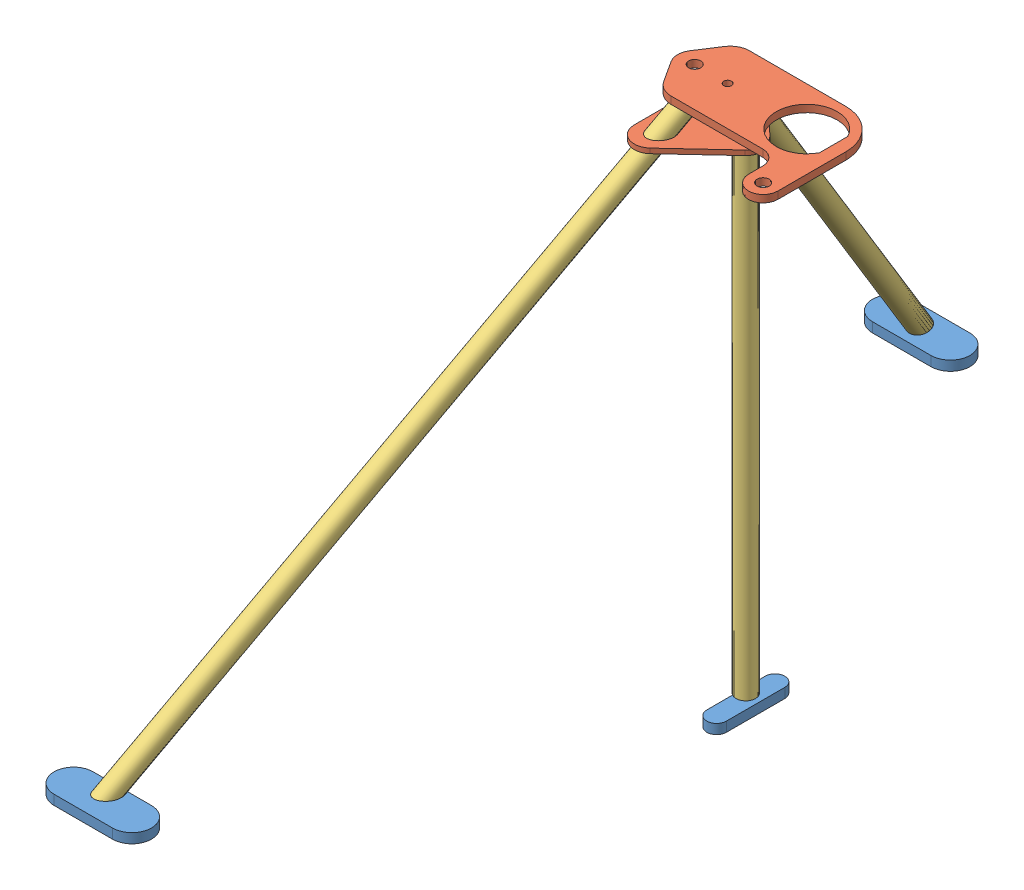
SolidWorks assembly RakedSensorMast, configuration Default. Lengths in mm.
Overall size (249.4 347.66 549.27).
4 component instances, 4 part files, 9 mates.
Components (placement in the parent):
- RakedSensorMastFeet-1: RakedSensorMastFeet [Default] x (-1 0 0) z (0 0 -1) size (190.5 342.9 549.27)
- RakedSensorMastTop-1: RakedSensorMastTop [Plates] x (-1 0 0) z (0 0 -1) size (109.7 26.99 94.83)
- RakedSensorMastTubes-1: RakedSensorMastTubes [Default] x (-1 0 0) z (0 0 -1) size (164.33 336.55 544.52)
- 91115A152_18-8 SS FEM THRDED HEX STANDOFF-1: 91115A152_18-8 SS FEM THRDED HEX STANDOFF [91115A151] at (-11.8541 -9.525 0) x (0 0 1) z (0 -1 0) size (6.35 7.33 19.71)
Mates (geometry in assembly coordinates):
- Concentric1: concentric anti-aligned: cylinder of RakedSensorMastFeet-1 through (-161.5757 -360.2726 -284.7157) axis (0.294384 0.76109 0.577997) radius 9.525; cylinder of RakedSensorMastTubes-1 through (-13.9451 21.4065 5.1443) axis (-0.294384 -0.76109 -0.577997) radius 6.35
- Concentric2: concentric anti-aligned: cylinder of RakedSensorMastFeet-1 through (-161.5757 -360.2726 284.7157) axis (0.294384 0.76109 -0.577997) radius 9.525; cylinder of RakedSensorMastTubes-1 through (-13.9451 21.4065 -5.1443) axis (-0.294384 -0.76109 0.577997) radius 6.35
- Concentric3: concentric anti-aligned: cylinder of RakedSensorMastTop-1 through (-36.4339 -36.7351 39.0104) axis (0.294384 0.76109 -0.577997) radius 6.35; cylinder of RakedSensorMastTubes-1 through (-13.9451 21.4065 -5.1443) axis (-0.294384 -0.76109 0.577997) radius 6.35
- Concentric4: concentric anti-aligned: cylinder of RakedSensorMastTop-1 through (-36.4339 -36.7351 -39.0104) axis (0.294384 0.76109 0.577997) radius 6.35; cylinder of RakedSensorMastTubes-1 through (-13.9451 21.4065 5.1443) axis (-0.294384 -0.76109 -0.577997) radius 6.35
- Concentric5: concentric anti-aligned: circle of RakedSensorMastTop-1; circle of 91115A152_18-8 SS FEM THRDED HEX STANDOFF-1
- Coincident1: coincident anti-aligned: plane of RakedSensorMastTop-1 through (0 -19.05 0) normal (0 1 0); plane of 91115A152_18-8 SS FEM THRDED HEX STANDOFF-1 through (-15.5202 -19.05 0) normal (0 -1 0)
- Coincident4: coincident anti-aligned: plane of RakedSensorMastTop-1 through (0 0 0) normal (0 0 -1); plane of assembly through (0 0 0) normal (0 0 1)
- Coincident5: coincident aligned: plane of RakedSensorMastTop-1 through (0 0 0) normal (0 1 0); plane of assembly through (0 0 0) normal (0 1 0)
- Coincident6: coincident anti-aligned: plane of RakedSensorMastTop-1 through (0 0 0) normal (-1 0 0); plane of assembly through (0 0 0) normal (1 0 0)
